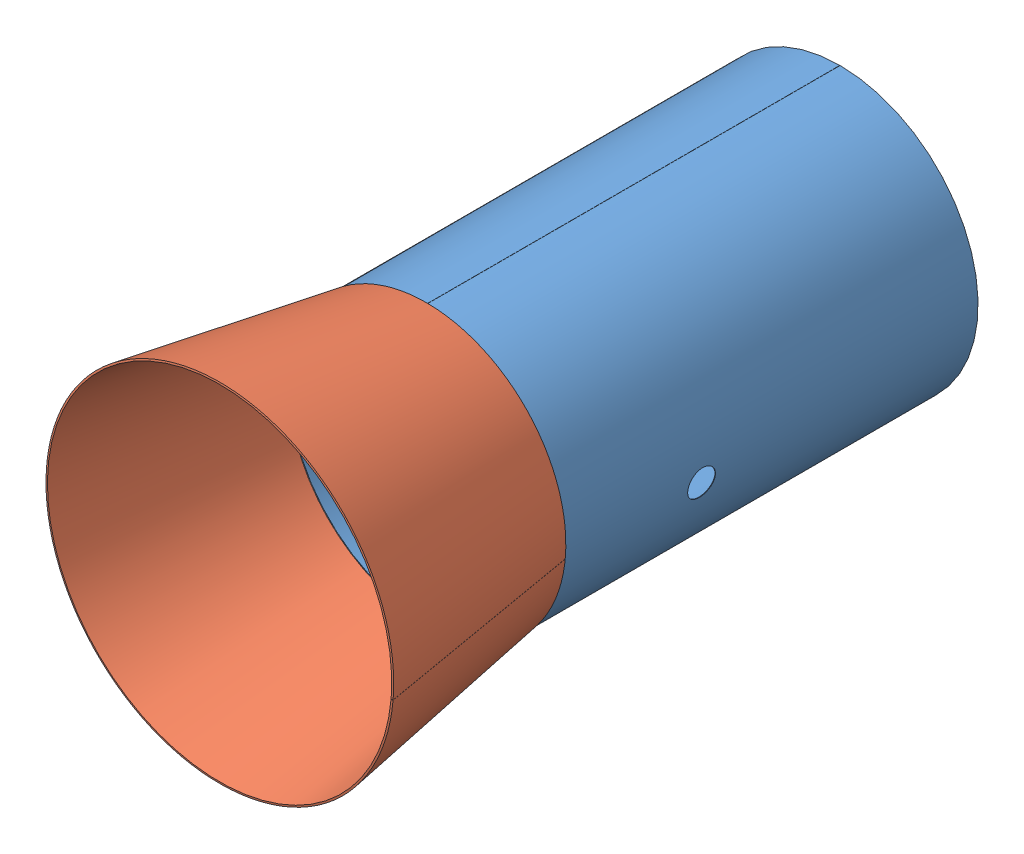
SolidWorks assembly Global Variable Assembly, configuration Default. Lengths in mm.
Overall size (2604.98 2604.92 4601).
2 component instances, 2 part files, 5 mates.
Components (placement in the parent):
- Pipe-1: Pipe [Default] at origin size (2038.86 2038.86 3048)
- Cone-1: Cone [Default] at (0 0 1528.572) size (2604.98 2604.92 1570.3)
Mates (geometry in assembly coordinates):
- Perpendicular1: perpendicular: plane of Cone-1 through (0 0 1528.572) normal (0 1 0); plane of assembly through (0 0 0) normal (1 0 0)
- Coincident1: coincident: plane of Cone-1 through (0 0 1528.572) normal (1 0 0); plane of assembly through (0 0 0) normal (1 0 0)
- Coincident2: coincident: plane of Cone-1 through (0 0 1528.572) normal (1 0 0); plane of assembly through (0 0 0) normal (1 0 0)
- Coincident3: coincident: plane of Cone-1 through (0 0 1528.572) normal (0 1 0); plane of assembly through (0 0 0) normal (0 1 0)
- Distance1: distance = 4.572 mm: plane of Cone-1 through (0 0 1528.572) normal (0 0 1); plane of Pipe-1 through (0 0 1524) normal (0 0 1)
